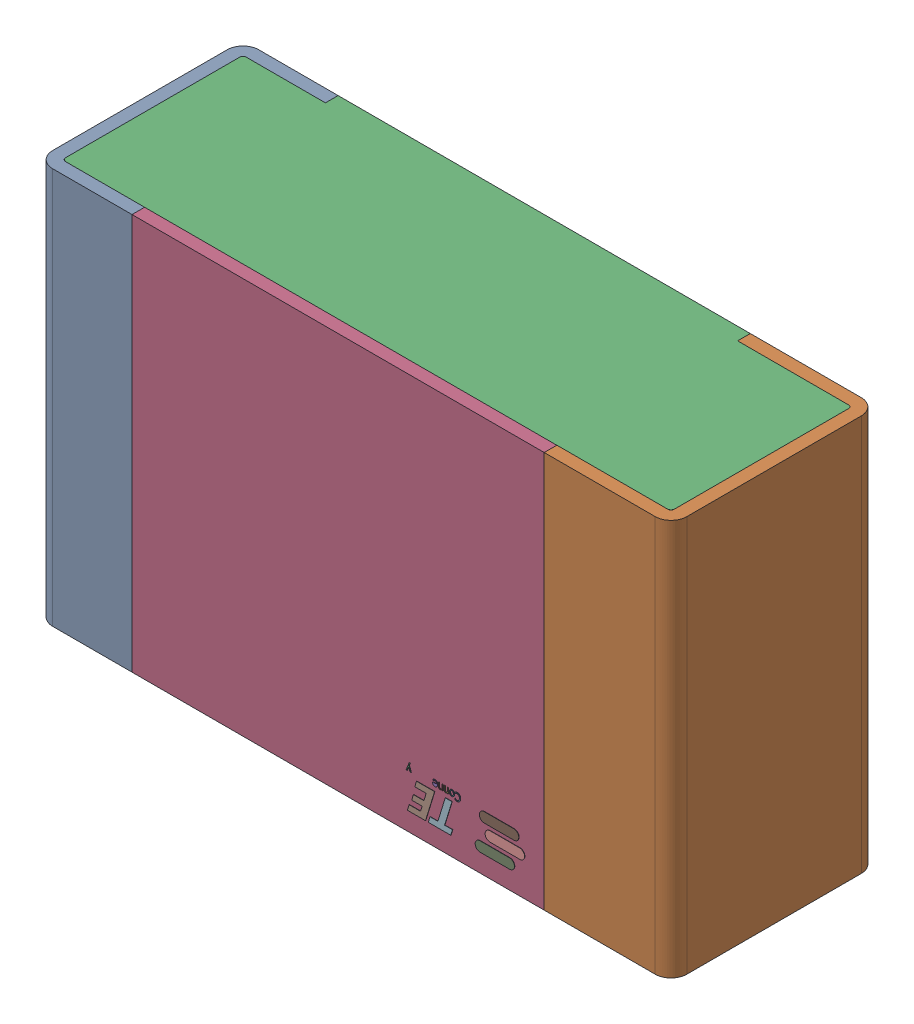
SolidWorks assembly RLH4.step, configuration Default. Lengths in mm.
Overall size (2 1.25 0.65).
5 component instances, 4 part files, 0 mates.
Components (placement in the parent):
- Res_TE_Connectivity_CPF0805B66R5E1_eec.step-1: Res_TE_Connectivity_CPF0805B66R5E1_eec.step [Default] at (5.191 10.287 0) x (-1 0 0) z (0 0 1) size (2 1.25 0.65)
  - 1.step-1: 1.step [Default] at origin size (2 1.25 0.65)
  - 2.step-1: 2.step [Default] at origin size (1.92 1.25 0.61)
  - 3.step-1: 3.step [Default] at origin size (1.3 1.25 0.04)
  - TE connectivity Logo 1 (2).step-1: TE connectivity Logo 1 (2).step [Default] at (5.4285 0.313 0.551) x (-1 0 0) z (0 0 1) size (0.37 0.13 0.11)
